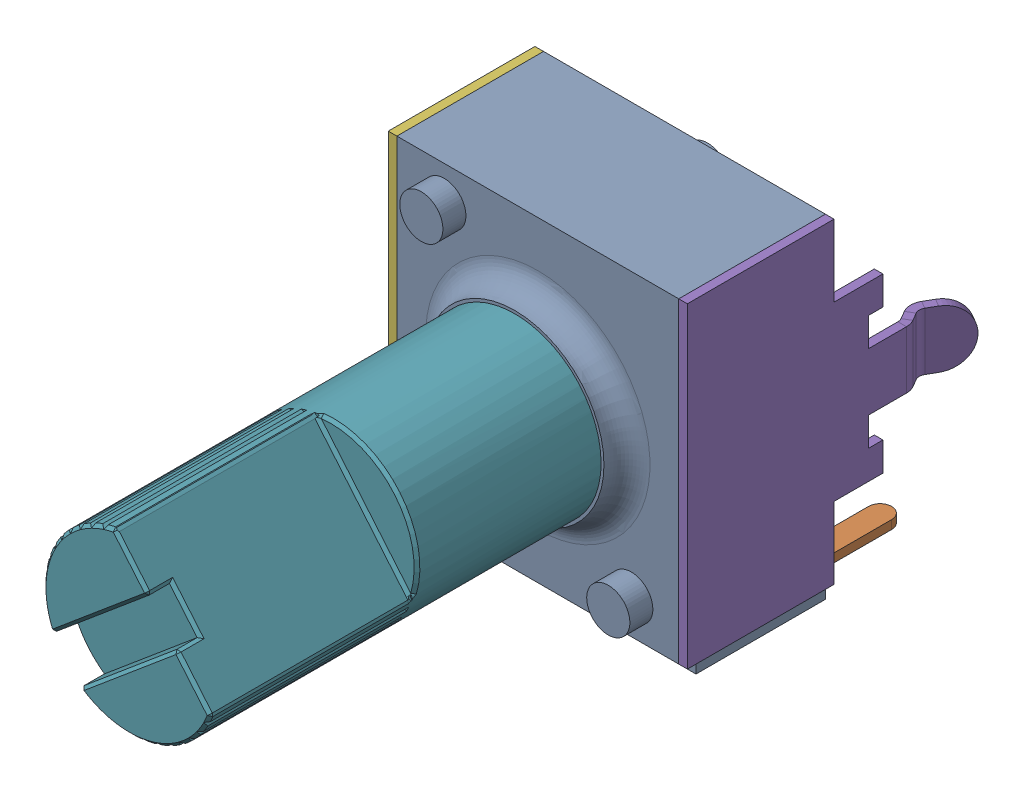
SolidWorks assembly R37_1.step, configuration Default. Lengths in mm.
Overall size (11.27 12.65 24.02).
7 component instances, 7 part files, 0 mates.
Components (placement in the parent):
- pot_1.step-11: pot_1.step [Default] at (355.95 288.1955 1.8) x (1 0 0) z (0 -1 0) size (9.8 6.7 11.6)
- pot-0_1.step-11: pot-0_1.step [Default] at (355.95 288.1955 1.8) x (1 0 0) z (0 -1 0) size (1.25 5.85 1.65)
- pot-1_1.step-11: pot-1_1.step [Default] at (355.95 288.1955 1.8) x (1 0 0) z (0 -1 0) size (1.25 5.85 1.65)
- pot-2_1.step-11: pot-2_1.step [Default] at (355.95 288.1955 1.8) x (1 0 0) z (0 -1 0) size (1.25 5.85 1.65)
- pot-3_1.step-11: pot-3_1.step [Default] at (355.95 288.1955 1.8) x (1 0 0) z (0 -1 0) size (1.02 9.82 11)
- pot-4_1.step-11: pot-4_1.step [Default] at (355.95 288.1955 1.8) x (1 0 0) z (0 -1 0) size (1.02 9.82 11)
- pot-5_1.step-11: pot-5_1.step [Default] at (355.95 288.1955 1.8) x (1 0 0) z (0 -1 0) size (6 14.2 6)
